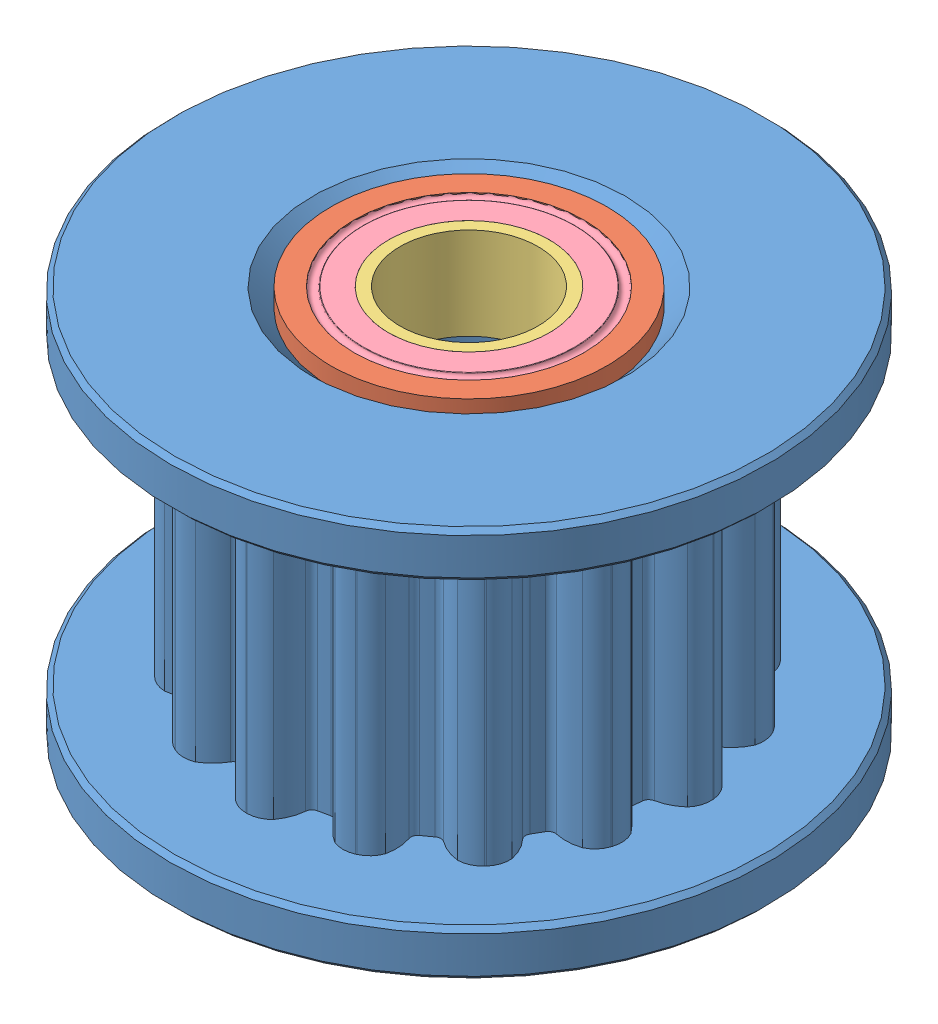
SolidWorks assembly GT2 Timing Idler Pulley, Configurable, configuration 16T W6 B3 With T. Lengths in mm.
Overall size (13 8.5 13).
27 component instances, 5 part files, 6 mates.
Components (placement in the parent):
- Body, GT2 Timing Idler Pulley, Configurable-1: Body, GT2 Timing Idler Pulley, Configurable [16T W6 B3 With T] x (-1 0 0) z (0 0 -1) size (13 8.5 13)
- Bearing Subassy, GT2 Timing Idler Pulley, Configurable-1: Bearing Subassy, GT2 Timing Idler Pulley, Configurable [3 mm Bore, 6 mm OD] at (0 3.25 0) size (6 2 6) (flexible)
  - Bearing Outer Ring, GT2 Timing Idler Pulley, Configurable-1: Bearing Outer Ring, GT2 Timing Idler Pulley, Configurable [3 mm Bore, 6 mm OD] at origin size (6 2 6)
  - Bearing Inner Ring, GT2 Timing Idler Pulley, Configurable-1: Bearing Inner Ring, GT2 Timing Idler Pulley, Configurable [3 mm Bore, 6 mm OD] x (0.841032 0 0.540986) z (-0.540986 0 0.841032) size (3.5 2 3.5)
  - Bearing Seal, GT2 Timing Idler Pulley, Configurable-1: Bearing Seal, GT2 Timing Idler Pulley, Configurable [3 mm Bore, 6 mm OD] at (0 0.75 0) size (5 0.5 5)
  - Bearing Seal, GT2 Timing Idler Pulley, Configurable-2: Bearing Seal, GT2 Timing Idler Pulley, Configurable [3 mm Bore, 6 mm OD] at (0 -0.75 0) x (1 0 0) z (0 0 -1) size (5 0.5 5)
  - Bearing Ball, GT2 Timing Idler Pulley, Configurable-1: Bearing Ball, GT2 Timing Idler Pulley, Configurable [1 mm] at (-1.9182 0 0.9145) x (0.828223 0 0.560398) z (-0.560398 0 0.828223) size (1 1 1)
  - Bearing Ball, GT2 Timing Idler Pulley, Configurable-2: Bearing Ball, GT2 Timing Idler Pulley, Configurable [1 mm] at (-2.003 0 -0.7097) x (0.189381 0 0.981904) z (-0.981904 0 0.189381) size (1 1 1)
  - Bearing Ball, GT2 Timing Idler Pulley, Configurable-3: Bearing Ball, GT2 Timing Idler Pulley, Configurable [1 mm] at (-0.9145 0 -1.9182) x (-0.560398 0 0.828223) z (-0.828223 0 -0.560398) size (1 1 1)
  - Bearing Ball, GT2 Timing Idler Pulley, Configurable-4: Bearing Ball, GT2 Timing Idler Pulley, Configurable [1 mm] at (0.7097 0 -2.003) x (-0.981904 0 0.189381) z (-0.189381 0 -0.981904) size (1 1 1)
  - Bearing Ball, GT2 Timing Idler Pulley, Configurable-5: Bearing Ball, GT2 Timing Idler Pulley, Configurable [1 mm] at (1.9182 0 -0.9145) x (-0.828223 0 -0.560398) z (0.560398 0 -0.828223) size (1 1 1)
  - Bearing Ball, GT2 Timing Idler Pulley, Configurable-6: Bearing Ball, GT2 Timing Idler Pulley, Configurable [1 mm] at (2.003 0 0.7097) x (-0.189381 0 -0.981904) z (0.981904 0 -0.189381) size (1 1 1)
  - Bearing Ball, GT2 Timing Idler Pulley, Configurable-7: Bearing Ball, GT2 Timing Idler Pulley, Configurable [1 mm] at (0.9145 0 1.9182) x (0.560398 0 -0.828223) z (0.828223 0 0.560398) size (1 1 1)
  - Bearing Ball, GT2 Timing Idler Pulley, Configurable-8: Bearing Ball, GT2 Timing Idler Pulley, Configurable [1 mm] at (-0.7097 0 2.003) x (0.981904 0 -0.189381) z (0.189381 0 0.981904) size (1 1 1)
- Bearing Subassy, GT2 Timing Idler Pulley, Configurable-2: Bearing Subassy, GT2 Timing Idler Pulley, Configurable [3 mm Bore, 6 mm OD] at (0 -3.25 0) x (1 0 0) z (0 0 -1) size (6 2 6) (flexible)
  - Bearing Outer Ring, GT2 Timing Idler Pulley, Configurable-1: Bearing Outer Ring, GT2 Timing Idler Pulley, Configurable [3 mm Bore, 6 mm OD] at origin size (6 2 6)
  - Bearing Inner Ring, GT2 Timing Idler Pulley, Configurable-1: Bearing Inner Ring, GT2 Timing Idler Pulley, Configurable [3 mm Bore, 6 mm OD] x (0.841032 0 0.540986) z (-0.540986 0 0.841032) size (3.5 2 3.5)
  - Bearing Seal, GT2 Timing Idler Pulley, Configurable-1: Bearing Seal, GT2 Timing Idler Pulley, Configurable [3 mm Bore, 6 mm OD] at (0 0.75 0) size (5 0.5 5)
  - Bearing Seal, GT2 Timing Idler Pulley, Configurable-2: Bearing Seal, GT2 Timing Idler Pulley, Configurable [3 mm Bore, 6 mm OD] at (0 -0.75 0) x (1 0 0) z (0 0 -1) size (5 0.5 5)
  - Bearing Ball, GT2 Timing Idler Pulley, Configurable-1: Bearing Ball, GT2 Timing Idler Pulley, Configurable [1 mm] at (-1.9182 0 0.9145) x (0.828223 0 0.560398) z (-0.560398 0 0.828223) size (1 1 1)
  - Bearing Ball, GT2 Timing Idler Pulley, Configurable-2: Bearing Ball, GT2 Timing Idler Pulley, Configurable [1 mm] at (-2.003 0 -0.7097) x (0.189381 0 0.981904) z (-0.981904 0 0.189381) size (1 1 1)
  - Bearing Ball, GT2 Timing Idler Pulley, Configurable-3: Bearing Ball, GT2 Timing Idler Pulley, Configurable [1 mm] at (-0.9145 0 -1.9182) x (-0.560398 0 0.828223) z (-0.828223 0 -0.560398) size (1 1 1)
  - Bearing Ball, GT2 Timing Idler Pulley, Configurable-4: Bearing Ball, GT2 Timing Idler Pulley, Configurable [1 mm] at (0.7097 0 -2.003) x (-0.981904 0 0.189381) z (-0.189381 0 -0.981904) size (1 1 1)
  - Bearing Ball, GT2 Timing Idler Pulley, Configurable-5: Bearing Ball, GT2 Timing Idler Pulley, Configurable [1 mm] at (1.9182 0 -0.9145) x (-0.828223 0 -0.560398) z (0.560398 0 -0.828223) size (1 1 1)
  - Bearing Ball, GT2 Timing Idler Pulley, Configurable-6: Bearing Ball, GT2 Timing Idler Pulley, Configurable [1 mm] at (2.003 0 0.7097) x (-0.189381 0 -0.981904) z (0.981904 0 -0.189381) size (1 1 1)
  - Bearing Ball, GT2 Timing Idler Pulley, Configurable-7: Bearing Ball, GT2 Timing Idler Pulley, Configurable [1 mm] at (0.9145 0 1.9182) x (0.560398 0 -0.828223) z (0.828223 0 0.560398) size (1 1 1)
  - Bearing Ball, GT2 Timing Idler Pulley, Configurable-8: Bearing Ball, GT2 Timing Idler Pulley, Configurable [1 mm] at (-0.7097 0 2.003) x (0.981904 0 -0.189381) z (0.189381 0 0.981904) size (1 1 1)
Mates (geometry in assembly coordinates):
- Coincident2: coincident: point of assembly; point of Body, GT2 Timing Idler Pulley, Configurable-1; point of assembly
- Coincident3: coincident: plane of assembly through (0 0 0) normal (0 1 0); plane of Body, GT2 Timing Idler Pulley, Configurable-1 through (0 0 0) normal (0 1 0); plane of assembly
- Concentric1: concentric: cylinder of assembly; cylinder of assembly; cylinder of Body, GT2 Timing Idler Pulley, Configurable-1 through (0 4.25 0) axis (0 1 0) radius 3; cylinder of Bearing Subassy, GT2 Timing Idler Pulley, Configurable-1/Bearing Outer Ring, GT2 Timing Idler Pulley, Configurable-1 through (0 4.25 0) axis (0 -1 0) radius 3
- Coincident4: coincident: plane of assembly; plane of assembly; plane of Body, GT2 Timing Idler Pulley, Configurable-1 through (-3 2.25 0) normal (0 1 0); plane of Bearing Subassy, GT2 Timing Idler Pulley, Configurable-1/Bearing Outer Ring, GT2 Timing Idler Pulley, Configurable-1 through (0 2.25 0) normal (0 -1 0)
- Coincident6: coincident: plane of Body, GT2 Timing Idler Pulley, Configurable-1 through (0 0 0) normal (-1 0 0); plane of Bearing Subassy, GT2 Timing Idler Pulley, Configurable-1/Bearing Outer Ring, GT2 Timing Idler Pulley, Configurable-1 through (0 3.25 0) normal (1 0 0)
- Coincident7: coincident: plane of assembly through (0 0 0) normal (0 0 1); plane of Body, GT2 Timing Idler Pulley, Configurable-1 through (0 0 0) normal (0 0 -1); plane of assembly
